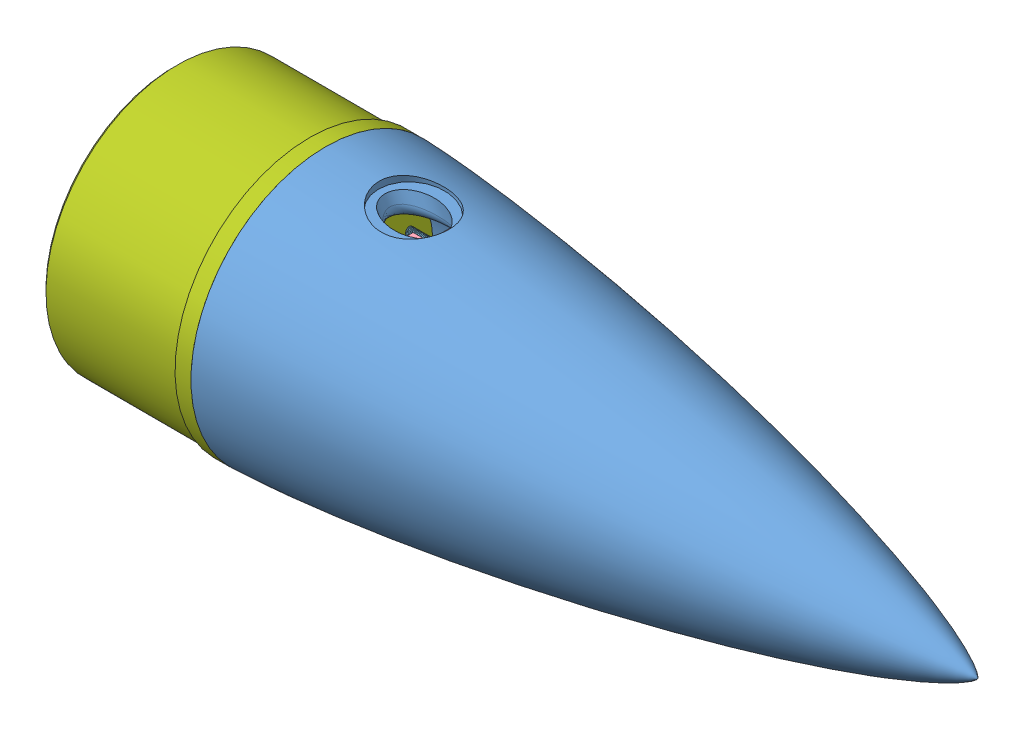
SolidWorks assembly Nosecone Assembly, configuration Default. Lengths in mm.
Overall size (504.08 230.99 230.99).
16 component instances, 7 part files, 15 mates.
Components (placement in the parent):
- Nosecone Prototype v5-1: Nosecone Prototype v5 [Default] at origin size (409.09 169.1 169.1)
- Nosecone Tap Insert-1: Nosecone Tap Insert [99362A500] at (10.691 34.775 60.2321) x (0 1 0) z (0 0 1) size (7.72 10.12 7.66)
- Nosecone Tap Insert-2: Nosecone Tap Insert [99362A500] at (10.691 -34.775 60.2321) x (0 0.5 0.866025) z (0 -0.866025 0.5) size (7.72 10.12 7.66)
- Nosecone Tap Insert-3: Nosecone Tap Insert [99362A500] at (10.691 -69.55 0) x (0 -0.5 0.866025) z (0 -0.866025 -0.5) size (7.72 10.12 7.66)
- Nosecone Tap Insert-4: Nosecone Tap Insert [99362A500] at (10.691 -34.775 -60.2321) x (0 -1 0) z (0 0 -1) size (7.72 10.12 7.66)
- Nosecone Tap Insert-5: Nosecone Tap Insert [99362A500] at (10.691 34.775 -60.2321) x (0 -0.5 -0.866025) z (0 0.866025 -0.5) size (7.72 10.12 7.66)
- Nosecone Tap Insert-6: Nosecone Tap Insert [99362A500] at (10.691 69.55 0) x (0 0.5 -0.866025) z (0 0.866025 0.5) size (7.72 10.12 7.66)
- Nosecone Plate Screw-1: Nosecone Plate Screw [92949A245] at (-12.1691 34.775 60.2321) x (0 0 1) z (-1 0 0) size (9.17 9.17 22.21)
- Nosecone Avionics v2-1: Nosecone Avionics v2 [Default] at (15.3953 1.1457 40.032) x (0 0.003855 -0.999993) z (0 -0.999993 -0.003855) size (122.08 21 32)
- Nosecone Avionics Nylon Bolt-1: Nosecone Avionics Nylon Bolt [99602A435] at (11.4056 12.5024 -52.4625) x (-1 0 0) z (0 -0.924225 -0.381849) size (29.17 9.24 8)
- Nosecone Avionics Nylon Bolt-2: Nosecone Avionics Nylon Bolt [99602A435] at (11.4056 12.0972 52.6119) x (-1 0 0) z (0 -0.924225 -0.381849) size (29.17 9.24 8)
- Nosecone Stainless Steel Hex Nut-1: Nosecone Stainless Steel Hex Nut [91240A411] at (-1.1922 12.5024 -52.4625) x (0 -1 0) z (0 0 1) size (9.53 3.67 11)
- Nosecone Stainless Steel Hex Nut-2: Nosecone Stainless Steel Hex Nut [91240A411] at (-1.1922 12.0972 52.6119) x (0 -1 0) z (0 0 1) size (9.53 3.67 11)
- Nosecone Stainless Steel Hex Nut-3: Nosecone Stainless Steel Hex Nut [91240A411] at (17.4181 12.0972 52.6119) x (0 1 0) z (0 0 1) size (9.53 3.67 11)
- Nosecone Stainless Steel Hex Nut-4: Nosecone Stainless Steel Hex Nut [91240A411] at (17.4181 12.5024 -52.4625) x (0 -1 0) z (0 0 1) size (9.53 3.67 11)
- NoseBottom-1: NoseBottom [Default] at (0.3963 0 0) x (0 0.5 -0.866025) z (1 0 0) size (169.1 169.1 95)
Mates (geometry in assembly coordinates):
- Coincident4: coincident anti-aligned: plane of Nosecone Avionics v2-1 through (22.0056 20.0351 -60.9335) normal (1 0 0); plane of Nosecone Avionics Nylon Bolt-1 through (22.0056 9.6873 -56.1243) normal (-1 0 0)
- Coincident5: coincident anti-aligned: plane of Nosecone Avionics v2-1 through (22.0056 19.5644 61.1408) normal (1 0 0); plane of Nosecone Avionics Nylon Bolt-2 through (22.0056 9.2822 48.9501) normal (-1 0 0)
- Concentric9: concentric anti-aligned: circle of Nosecone Avionics Nylon Bolt-1; circle of Nosecone Stainless Steel Hex Nut-1
- Concentric10: concentric anti-aligned: circle of Nosecone Avionics Nylon Bolt-2; circle of Nosecone Stainless Steel Hex Nut-2
- Concentric11: concentric anti-aligned: circle of Nosecone Avionics Nylon Bolt-1; circle of Nosecone Stainless Steel Hex Nut-4
- Coincident9: coincident anti-aligned: plane of Nosecone Avionics v2-1 through (19.0056 20.0351 -60.9335) normal (-1 0 0); plane of Nosecone Stainless Steel Hex Nut-4 through (19.0056 17.2649 -55.2121) normal (1 0 0)
- Coincident10: coincident anti-aligned: plane of Nosecone Avionics v2-1 through (19.0056 19.5644 61.1408) normal (-1 0 0); plane of Nosecone Stainless Steel Hex Nut-3 through (19.0056 7.3347 49.8623) normal (1 0 0)
- Concentric12: concentric aligned: circle of Nosecone Avionics Nylon Bolt-2; circle of Nosecone Stainless Steel Hex Nut-3
- Concentric13: concentric anti-aligned: cylinder of Nosecone Prototype v5-1 through (0.3953 34.775 60.2321) axis (-1 0 0) radius 3.3782; circle of Nosecone Tap Insert-1
- Lock1: lock: unknown of Nosecone Prototype v5-1; unknown of Nosecone Tap Insert-1
- Coincident11: coincident anti-aligned: plane of Nosecone Prototype v5-1 through (0.3953 69.55 0) normal (-1 0 0); plane of NoseBottom-1 through (0.3953 -42.275 73.2224) normal (1 0 0)
- Concentric15: concentric anti-aligned: cylinder of Nosecone Prototype v5-1 through (444.767 0 0) axis (1 0 0) radius 64.55; cylinder of NoseBottom-1 through (-99.3537 0 0) axis (-1 0 0) radius 82.55
- Concentric16: concentric aligned: circle of Nosecone Tap Insert-2; cylinder of NoseBottom-1 through (0.3963 -34.775 60.2321) axis (-1 0 0) radius 2.41
- Coincident12: coincident anti-aligned: plane of Nosecone Plate Screw-1 through (-9.6037 30.1903 60.2321) normal (1 0 0); plane of NoseBottom-1 through (-9.6037 8.0983 33.8189) normal (-1 0 0)
- Concentric17: concentric aligned: circle of Nosecone Plate Screw-1; cylinder of NoseBottom-1 through (0.3963 34.775 60.2321) axis (-1 0 0) radius 2.41
